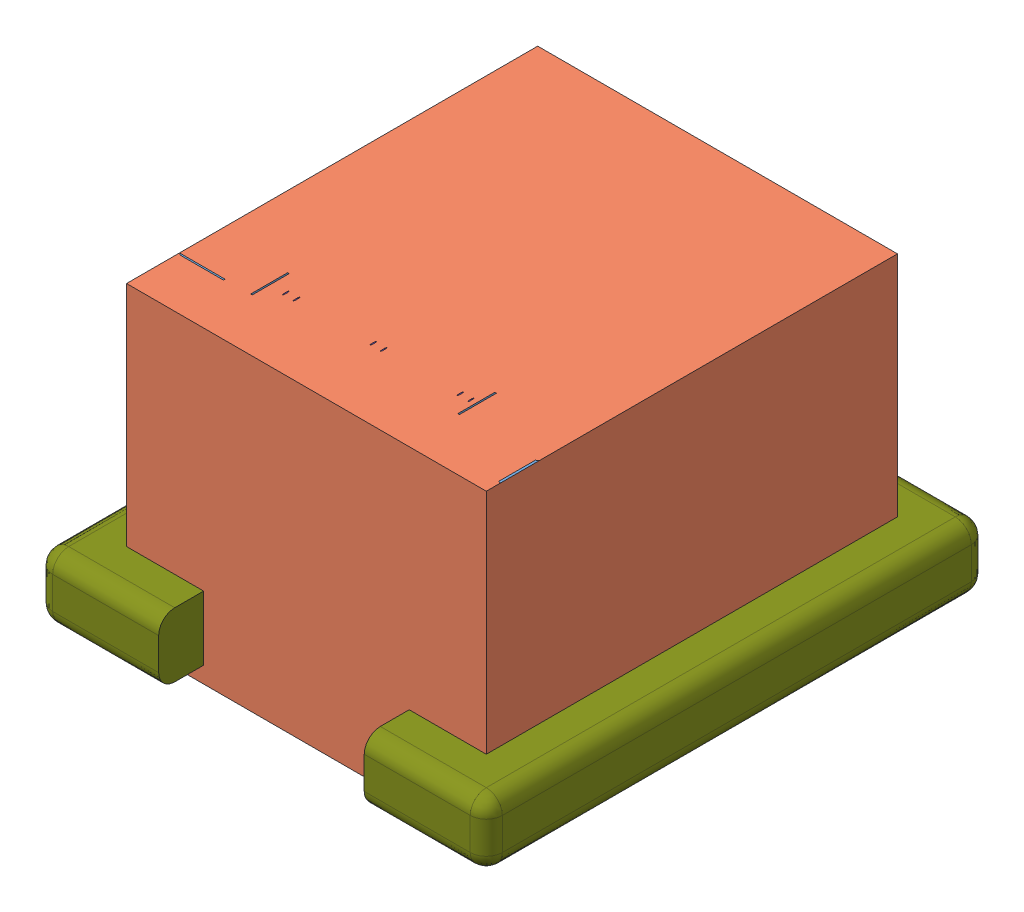
SolidWorks assembly BottyPotty, configuration Default. Lengths in mm.
Overall size (889 639.7 990.6).
139 component instances, 34 part files, 31 mates.
Components (placement in the parent):
- Gear Bit-1: Gear Bit [Default] at (72.3018 220.1757 180.7351) size (711.2 482.6 76.2)
- BoxBot-1: BoxBot [Default] at (72.3018 251.9257 -158.9899) size (711.2 609.6 812.8)
- Fuel-1: Fuel [Default] at (72.3018 234.1474 -212.6616) size (127 127 127)
- Bin-1: Bin [Default] at (72.3018 315.4257 -311.3899) size (711.2 482.6 508)
- Climby Bit-1: Climby Bit [Default] at (72.3018 137.6257 -463.7899) size (304.8 127 203.2)
- Gear-1: Gear [Default] at (72.3018 207.6033 181.9111) size (279.4 279.4 50.8)
- Collection-1: Collection [Default] at (-247.2786 -102.69 264.2469) x (0 0 -1) z (1 0 0) size (103.22 501.51 473.08)
  - HexRod-1: HexRod [Default] at (158.1244 213.3282 311.0594) size (12.7 14.66 406.4)
  - wheelpulley-1: wheelpulley [Default] at (101.3185 233.0041 546.741) x (0 0 -1) z (0.052324 -0.99863 0) size (42.43 76.75 76.75)
    - pulley-1: pulley [Default] at (45.3639 55.6985 22.6212) size (13 74.23 74.23)
    - pulley-2: pulley [Default] at (62.0263 55.6985 22.6212) x (-1 0 0) z (0 0.000084 1) size (13 74.23 74.23)
    - wheel-1: wheel [Default] at (70.1462 55.6985 22.6212) x (1 0 0) z (0 -0.99863 -0.052324) size (9.53 73.03 73.03)
    - wheel-2: wheel [Default] at (37.244 55.6985 22.6212) x (1 0 0) z (0 -0.99863 -0.052324) size (9.53 73.03 73.03)
  - wheelpulley-2: wheelpulley [Default] at (101.3185 233.0041 374.275) x (0 0 -1) z (0.052324 -0.99863 0) size (42.43 76.75 76.75)
    - pulley-1: pulley [Default] at (45.3639 55.6985 22.6212) size (13 74.23 74.23)
    - pulley-2: pulley [Default] at (62.0263 55.6985 22.6212) x (-1 0 0) z (0 0.000084 1) size (13 74.23 74.23)
    - wheel-1: wheel [Default] at (70.1462 55.6985 22.6212) x (1 0 0) z (0 -0.99863 -0.052324) size (9.53 73.03 73.03)
    - wheel-2: wheel [Default] at (37.244 55.6985 22.6212) x (1 0 0) z (0 -0.99863 -0.052324) size (9.53 73.03 73.03)
  - wheelpulley-3: wheelpulley [Default] at (101.3185 233.0041 201.809) x (0 0 -1) z (0.052324 -0.99863 0) size (42.43 76.75 76.75)
    - pulley-1: pulley [Default] at (45.3639 55.6985 22.6212) size (13 74.23 74.23)
    - pulley-2: pulley [Default] at (62.0263 55.6985 22.6212) x (-1 0 0) z (0 0.000084 1) size (13 74.23 74.23)
    - wheel-1: wheel [Default] at (70.1462 55.6985 22.6212) x (1 0 0) z (0 -0.99863 -0.052324) size (9.53 73.03 73.03)
    - wheel-2: wheel [Default] at (37.244 55.6985 22.6212) x (1 0 0) z (0 -0.99863 -0.052324) size (9.53 73.03 73.03)
  - wheelplate-1: wheelplate [Default] at (158.1244 213.3282 515.8469) x (0 0 -1) z (1 0 0) size (3.17 482.6 73.03)
  - wheelplate-2: wheelplate [Default] at (158.1244 213.3282 106.2719) x (0 0 -1) z (1 0 0) size (3.17 482.6 73.03)
  - CollectSub-1: CollectSub [Default] at (376.0703 456.2047 78.0182) size (103.22 103.22 450.86)
    - HexRod-1: HexRod [Default] at (-217.9459 166.6985 296.5412) size (12.7 14.66 406.4)
    - wheelpulley-1: wheelpulley [Default] at (-263.3886 127.3412 468.7227) x (0 0 -1) z (0.891001 -0.454001 0) size (42.43 76.75 76.75)
      - pulley-1: pulley [Default] at (45.3639 55.6985 22.6212) size (13 74.23 74.23)
      - pulley-2: pulley [Default] at (62.0263 55.6985 22.6212) x (-1 0 0) z (0 0.000084 1) size (13 74.23 74.23)
      - wheel-1: wheel [Default] at (70.1462 55.6985 22.6212) x (1 0 0) z (0 -0.99863 -0.052324) size (9.53 73.03 73.03)
      - wheel-2: wheel [Default] at (37.244 55.6985 22.6212) x (1 0 0) z (0 -0.99863 -0.052324) size (9.53 73.03 73.03)
    - wheelpulley-2: wheelpulley [Default] at (-263.3886 127.3412 296.2567) x (0 0 -1) z (0.891001 -0.454001 0) size (42.43 76.75 76.75)
      - pulley-1: pulley [Default] at (45.3639 55.6985 22.6212) size (13 74.23 74.23)
      - pulley-2: pulley [Default] at (62.0263 55.6985 22.6212) x (-1 0 0) z (0 0.000084 1) size (13 74.23 74.23)
      - wheel-1: wheel [Default] at (70.1462 55.6985 22.6212) x (1 0 0) z (0 -0.99863 -0.052324) size (9.53 73.03 73.03)
      - wheel-2: wheel [Default] at (37.244 55.6985 22.6212) x (1 0 0) z (0 -0.99863 -0.052324) size (9.53 73.03 73.03)
    - wheelpulley-3: wheelpulley [Default] at (-263.3886 127.3412 123.7907) x (0 0 -1) z (0.891001 -0.454001 0) size (42.43 76.75 76.75)
      - pulley-1: pulley [Default] at (45.3639 55.6985 22.6212) size (13 74.23 74.23)
      - pulley-2: pulley [Default] at (62.0263 55.6985 22.6212) x (-1 0 0) z (0 0.000084 1) size (13 74.23 74.23)
      - wheel-1: wheel [Default] at (70.1462 55.6985 22.6212) x (1 0 0) z (0 -0.99863 -0.052324) size (9.53 73.03 73.03)
      - wheel-2: wheel [Default] at (37.244 55.6985 22.6212) x (1 0 0) z (0 -0.99863 -0.052324) size (9.53 73.03 73.03)
  - Belt-gates 10mm wide-2: Belt-gates 10mm wide [Default] at (158.1371 418.0522 319.5804) x (0 0 1) z (0.000062 -1 0) size (15 69.9 479.58)
  - Belt-gates 10mm wide-3: Belt-gates 10mm wide [Default] at (158.1371 418.0522 491.638) x (0 0 1) z (0.000062 -1 0) size (15 69.9 479.58)
  - Belt-gates 10mm wide-4: Belt-gates 10mm wide [Default] at (158.1371 418.0522 149.5217) x (0 0 1) z (0.000062 -1 0) size (15 69.9 479.58)
- ball ramp-1: ball ramp [Default] at (72.3018 110.6382 106.1226) size (711.2 452.32 91.84)
- 2017 electronics plate-1: 2017 electronics plate [Default] at (72.3018 42.3757 -311.3899) x (1 0 0) z (0 0 -1) size (711.2 41.27 812.8)
  - electronics plate-1: electronics plate [Default] at origin size (711.2 3.17 812.8)
  - Victor-SP-Motor-controller-20217-9090-1: Victor-SP-Motor-controller-20217-9090 [Default] at (-258.5801 9.1448 -219.6738) size (30.24 20.93 144.78)
  - Victor-SP-Motor-controller-20217-9090-3: Victor-SP-Motor-controller-20217-9090 [Default] at (-215.4001 9.1448 -219.6738) size (30.24 20.93 144.78)
  - Victor-SP-Motor-controller-20217-9090-4: Victor-SP-Motor-controller-20217-9090 [Default] at (-172.2201 9.1448 -219.6738) size (30.24 20.93 144.78)
  - Victor-SP-Motor-controller-20217-9090-5: Victor-SP-Motor-controller-20217-9090 [Default] at (-129.0401 9.1448 -219.6738) size (30.24 20.93 144.78)
  - VoltReg-217-4245-1: VoltReg-217-4245 [Default] at (-39.4381 10.281 -153.6848) size (56.39 19.92 51.56)
  - RouterCrude-1: RouterCrude [Default] at (37.6355 15.875 -155.8516) size (66.67 25.4 92.08)
  - PowerDistribution-1: PowerDistribution [Default] at (-149.0064 9.8552 -39.9983) x (-1 0 0) z (0 0 -1) size (192.68 36.15 120.93)
  - Victor-SP-Motor-controller-20217-9090-9: Victor-SP-Motor-controller-20217-9090 [Default] at (122.4199 9.1448 -219.6738) size (30.24 20.93 144.78)
  - Victor-SP-Motor-controller-20217-9090-10: Victor-SP-Motor-controller-20217-9090 [Default] at (165.5999 9.1448 -219.6738) size (30.24 20.93 144.78)
  - Victor-SP-Motor-controller-20217-9090-11: Victor-SP-Motor-controller-20217-9090 [Default] at (208.7799 9.1448 -219.6738) size (30.24 20.93 144.78)
  - Victor-SP-Motor-controller-20217-9090-12: Victor-SP-Motor-controller-20217-9090 [Default] at (251.9599 9.1448 -219.6738) size (30.24 20.93 144.78)
  - RoboRIO-1: RoboRIO [Default] at (170.9718 13.675 -32.4938) x (0.999904 0 0.013829) z (-0.013829 0 0.999904) size (147 34 144)
- Drive Side 32- version current 1-20-17-1: Drive Side 32- version current 1-20-17 [Default] at (333.5386 -44.9466 -117.3546) x (0 0 1) z (0 1 0) size (812.8 264.42 101.6)
  - Part 1_1-1: Part 1_1 [Default] at (-41.6353 24.5131 42.8723) size (812.8 6.35 82.55)
  - Part 1_1_2-1: Part 1_1_2 [Default] at (-41.6353 94.3631 42.8723) size (812.8 6.35 82.55)
  - Part 5_1-1: Part 5_1 [Default] at (-293.1186 5.1631 48.3276) x (0 0 -1) z (1 0 0) size (62.86 145.05 62.86)
  - Part 5_1-2: Part 5_1 [Default] at (-47.0906 5.1631 32.689) size (62.86 145.05 62.86)
  - am-0255 2.5inch CIM Motor_1-1: am-0255 2.5inch CIM Motor_1 [Default] at (-318.4953 -64.3869 152.1685) x (1 0 0) z (0 1 0) size (64.01 64.01 154.94)
  - am-0255 2.5inch CIM Motor_1-2: am-0255 2.5inch CIM Motor_1 [Default] at (-77.1953 -64.3869 152.1685) x (1 0 0) z (0 1 0) size (64.01 64.01 154.94)
  - 4 in tread_1-1: 4 in tread_1 [Default] at (-282.9353 63.8121 42.8723) x (0 1 0) z (0 0 1) size (25.4 101.6 101.6)
  - 4in 2013 Hub_1-1: 4in 2013 Hub_1 [Default] at (-282.9353 63.8121 42.8723) x (0 1 0) z (1 0 0) size (17.56 82.55 82.55)
  - 4in 2013 Hub_1_2-1: 4in 2013 Hub_1_2 [Default] at (-282.9353 63.8121 42.8723) x (0 1 0) z (1 0 0) size (17.56 82.55 82.55)
  - 4 in tread_1-2: 4 in tread_1 [Default] at (-41.6353 67.1549 42.8723) x (0 -1 0) z (0 0 1) size (25.4 101.6 101.6)
  - 4in 2013 Hub_1-2: 4in 2013 Hub_1 [Default] at (-41.6353 67.1549 42.8723) x (0 1 0) z (1 0 0) size (17.56 82.55 82.55)
  - 4in 2013 Hub_1_2-2: 4in 2013 Hub_1_2 [Default] at (-41.6353 67.1549 42.8723) x (0 1 0) z (1 0 0) size (17.56 82.55 82.55)
  - am-0030 0.5''''id Flanged, Shielded Ball Bearing (FR8ZZ)_1-1: am-0030 0.5''''id Flanged, Shielded Ball Bearing (FR8ZZ)_1 [Default] at (-41.6353 94.4165 42.8723) x (1 0 0) z (0 -1 0) size (31.12 31.12 7.93)
  - am-0030 0.5''''id Flanged, Shielded Ball Bearing (FR8ZZ)_1-2: am-0030 0.5''''id Flanged, Shielded Ball Bearing (FR8ZZ)_1 [Default] at (-41.6353 18.1098 42.8723) x (1 0 0) z (0 1 0) size (31.12 31.12 7.93)
  - am-0030 0.5''''id Flanged, Shielded Ball Bearing (FR8ZZ)_1-3: am-0030 0.5''''id Flanged, Shielded Ball Bearing (FR8ZZ)_1 [Default] at (-282.9353 94.4165 42.8723) x (1 0 0) z (0 -1 0) size (31.12 31.12 7.93)
  - P60 bearing block_1-1: P60 bearing block_1 [Default] at (184.6301 84.0337 22.2734) x (0 1 0) z (1 0 0) size (9.02 38.25 38.25)
  - R8ZZ Bearing_1-1: R8ZZ Bearing_1 [Default] at (220.2635 84.3512 27.8377) x (0 1 0) z (0 0 1) size (7.94 28.58 28.58)
  - P60 bearing block_1-2: P60 bearing block_1 [Default] at (184.6301 28.4926 63.4711) x (0 -1 0) z (1 0 0) size (9.02 38.25 38.25)
  - R8ZZ Bearing_1-2: R8ZZ Bearing_1 [Default] at (220.2635 139.9137 27.8377) x (0 1 0) z (0 0 1) size (7.94 28.58 28.58)
  - 500 Key Hub r2_1-1: 500 Key Hub r2_1 [Default] at (-282.9353 80.3856 42.8723) x (-1 0 0) z (0 1 0) size (57.15 57.15 25.4)
  - 500 Key Hub r2_1-2: 500 Key Hub r2_1 [Default] at (-41.6353 50.5814 42.8723) x (1 0 0) z (0 -1 0) size (57.15 57.15 25.4)
  - 500 Key Hub r2_1-3: 500 Key Hub r2_1 [Default] at (-282.9353 47.2386 42.8723) x (1 0 0) z (0 -1 0) size (57.15 57.15 25.4)
  - 500 Key Hub r2_1-4: 500 Key Hub r2_1 [Default] at (-41.6353 83.7284 42.8723) x (-1 0 0) z (0 1 0) size (57.15 57.15 25.4)
  - am-0030 0.5''''id Flanged, Shielded Ball Bearing (FR8ZZ)_1-4: am-0030 0.5''''id Flanged, Shielded Ball Bearing (FR8ZZ)_1 [Default] at (-282.9353 18.1098 42.8723) x (1 0 0) z (0 1 0) size (31.12 31.12 7.93)
  - 217-2736.20121205_1-1: 217-2736.20121205_1 [Default] at (-37.0221 40.4543 45.4879) x (1 0 0) z (0 1 0) size (25.39 25.4 6.35)
  - 217-2736.20121205_1-2: 217-2736.20121205_1 [Default] at (-37.0221 93.8554 40.2567) x (1 0 0) z (0 -1 0) size (25.39 25.4 6.35)
  - 217-2736.20121205_1-3: 217-2736.20121205_1 [Default] at (-278.3221 37.1115 45.4879) x (1 0 0) z (0 1 0) size (25.39 25.4 6.35)
  - 217-2736.20121205_1-4: 217-2736.20121205_1 [Default] at (-278.3221 90.5127 40.2567) x (1 0 0) z (0 -1 0) size (25.39 25.4 6.35)
  - am-churro 500 churro tube_1-1: am-churro 500 churro tube_1 [Default] at (-435.3353 24.5131 68.9073) x (1 0 0) z (0 1 0) size (14.66 12.7 63.5)
  - am-churro 500 churro tube_1-2: am-churro 500 churro tube_1 [Default] at (-435.3353 24.5131 16.8373) x (1 0 0) z (0 1 0) size (14.66 12.7 63.5)
  - am-churro 500 churro tube_1-3: am-churro 500 churro tube_1 [Default] at (352.0647 24.5131 68.9073) x (1 0 0) z (0 1 0) size (14.66 12.7 63.5)
  - am-churro 500 churro tube_1-4: am-churro 500 churro tube_1 [Default] at (352.0647 24.5131 16.8373) x (1 0 0) z (0 1 0) size (14.66 12.7 63.5)
  - am-churro 500 churro tube_1-5: am-churro 500 churro tube_1 [Default] at (-162.2853 24.5131 16.8373) x (1 0 0) z (0 1 0) size (14.66 12.7 63.5)
  - am-churro 500 churro tube_1-6: am-churro 500 churro tube_1 [Default] at (79.0147 24.5131 68.9073) x (1 0 0) z (0 1 0) size (14.66 12.7 63.5)
  - am-churro 500 churro tube_1-7: am-churro 500 churro tube_1 [Default] at (79.0147 24.5131 16.8373) x (1 0 0) z (0 1 0) size (14.66 12.7 63.5)
  - am-churro 500 churro tube_1-8: am-churro 500 churro tube_1 [Default] at (-162.2853 24.5131 68.9073) x (1 0 0) z (0 1 0) size (14.66 12.7 63.5)
- Drive Side 32- version current 1-20-17-2: Drive Side 32- version current 1-20-17 [Default] at (-188.9351 40.798 -117.3546) x (0 0 1) z (0 -1 0) size (812.8 264.42 101.6)
  - Part 1_1-1: Part 1_1 [Default] at (-41.6353 24.5131 42.8723) size (812.8 6.35 82.55)
  - Part 1_1_2-1: Part 1_1_2 [Default] at (-41.6353 94.3631 42.8723) size (812.8 6.35 82.55)
  - Part 5_1-1: Part 5_1 [Default] at (-293.1186 5.1631 48.3276) x (0 0 -1) z (1 0 0) size (62.86 145.05 62.86)
  - Part 5_1-2: Part 5_1 [Default] at (-47.0906 5.1631 32.689) size (62.86 145.05 62.86)
  - am-0255 2.5inch CIM Motor_1-1: am-0255 2.5inch CIM Motor_1 [Default] at (-318.4953 -64.3869 152.1685) x (1 0 0) z (0 1 0) size (64.01 64.01 154.94)
  - am-0255 2.5inch CIM Motor_1-2: am-0255 2.5inch CIM Motor_1 [Default] at (-77.1953 -64.3869 152.1685) x (1 0 0) z (0 1 0) size (64.01 64.01 154.94)
  - 4 in tread_1-1: 4 in tread_1 [Default] at (-282.9353 63.8121 42.8723) x (0 1 0) z (0 0 1) size (25.4 101.6 101.6)
  - 4in 2013 Hub_1-1: 4in 2013 Hub_1 [Default] at (-282.9353 63.8121 42.8723) x (0 1 0) z (1 0 0) size (17.56 82.55 82.55)
  - 4in 2013 Hub_1_2-1: 4in 2013 Hub_1_2 [Default] at (-282.9353 63.8121 42.8723) x (0 1 0) z (1 0 0) size (17.56 82.55 82.55)
  - 4 in tread_1-2: 4 in tread_1 [Default] at (-41.6353 67.1549 42.8723) x (0 -1 0) z (0 0 1) size (25.4 101.6 101.6)
  - 4in 2013 Hub_1-2: 4in 2013 Hub_1 [Default] at (-41.6353 67.1549 42.8723) x (0 1 0) z (1 0 0) size (17.56 82.55 82.55)
  - 4in 2013 Hub_1_2-2: 4in 2013 Hub_1_2 [Default] at (-41.6353 67.1549 42.8723) x (0 1 0) z (1 0 0) size (17.56 82.55 82.55)
  - am-0030 0.5''''id Flanged, Shielded Ball Bearing (FR8ZZ)_1-1: am-0030 0.5''''id Flanged, Shielded Ball Bearing (FR8ZZ)_1 [Default] at (-41.6353 94.4165 42.8723) x (1 0 0) z (0 -1 0) size (31.12 31.12 7.93)
  - am-0030 0.5''''id Flanged, Shielded Ball Bearing (FR8ZZ)_1-2: am-0030 0.5''''id Flanged, Shielded Ball Bearing (FR8ZZ)_1 [Default] at (-41.6353 18.1098 42.8723) x (1 0 0) z (0 1 0) size (31.12 31.12 7.93)
  - am-0030 0.5''''id Flanged, Shielded Ball Bearing (FR8ZZ)_1-3: am-0030 0.5''''id Flanged, Shielded Ball Bearing (FR8ZZ)_1 [Default] at (-282.9353 94.4165 42.8723) x (1 0 0) z (0 -1 0) size (31.12 31.12 7.93)
  - P60 bearing block_1-1: P60 bearing block_1 [Default] at (184.6301 84.0337 22.2734) x (0 1 0) z (1 0 0) size (9.02 38.25 38.25)
  - R8ZZ Bearing_1-1: R8ZZ Bearing_1 [Default] at (220.2635 84.3512 27.8377) x (0 1 0) z (0 0 1) size (7.94 28.58 28.58)
  - P60 bearing block_1-2: P60 bearing block_1 [Default] at (184.6301 28.4926 63.4711) x (0 -1 0) z (1 0 0) size (9.02 38.25 38.25)
  - R8ZZ Bearing_1-2: R8ZZ Bearing_1 [Default] at (220.2635 139.9137 27.8377) x (0 1 0) z (0 0 1) size (7.94 28.58 28.58)
  - 500 Key Hub r2_1-1: 500 Key Hub r2_1 [Default] at (-282.9353 80.3856 42.8723) x (-1 0 0) z (0 1 0) size (57.15 57.15 25.4)
  - 500 Key Hub r2_1-2: 500 Key Hub r2_1 [Default] at (-41.6353 50.5814 42.8723) x (1 0 0) z (0 -1 0) size (57.15 57.15 25.4)
  - 500 Key Hub r2_1-3: 500 Key Hub r2_1 [Default] at (-282.9353 47.2386 42.8723) x (1 0 0) z (0 -1 0) size (57.15 57.15 25.4)
  - 500 Key Hub r2_1-4: 500 Key Hub r2_1 [Default] at (-41.6353 83.7284 42.8723) x (-1 0 0) z (0 1 0) size (57.15 57.15 25.4)
  - am-0030 0.5''''id Flanged, Shielded Ball Bearing (FR8ZZ)_1-4: am-0030 0.5''''id Flanged, Shielded Ball Bearing (FR8ZZ)_1 [Default] at (-282.9353 18.1098 42.8723) x (1 0 0) z (0 1 0) size (31.12 31.12 7.93)
  - 217-2736.20121205_1-1: 217-2736.20121205_1 [Default] at (-37.0221 40.4543 45.4879) x (1 0 0) z (0 1 0) size (25.39 25.4 6.35)
  - 217-2736.20121205_1-2: 217-2736.20121205_1 [Default] at (-37.0221 93.8554 40.2567) x (1 0 0) z (0 -1 0) size (25.39 25.4 6.35)
  - 217-2736.20121205_1-3: 217-2736.20121205_1 [Default] at (-278.3221 37.1115 45.4879) x (1 0 0) z (0 1 0) size (25.39 25.4 6.35)
  - 217-2736.20121205_1-4: 217-2736.20121205_1 [Default] at (-278.3221 90.5127 40.2567) x (1 0 0) z (0 -1 0) size (25.39 25.4 6.35)
  - am-churro 500 churro tube_1-1: am-churro 500 churro tube_1 [Default] at (-435.3353 24.5131 68.9073) x (1 0 0) z (0 1 0) size (14.66 12.7 63.5)
  - am-churro 500 churro tube_1-2: am-churro 500 churro tube_1 [Default] at (-435.3353 24.5131 16.8373) x (1 0 0) z (0 1 0) size (14.66 12.7 63.5)
  - am-churro 500 churro tube_1-3: am-churro 500 churro tube_1 [Default] at (352.0647 24.5131 68.9073) x (1 0 0) z (0 1 0) size (14.66 12.7 63.5)
  - am-churro 500 churro tube_1-4: am-churro 500 churro tube_1 [Default] at (352.0647 24.5131 16.8373) x (1 0 0) z (0 1 0) size (14.66 12.7 63.5)
  - am-churro 500 churro tube_1-5: am-churro 500 churro tube_1 [Default] at (-162.2853 24.5131 16.8373) x (1 0 0) z (0 1 0) size (14.66 12.7 63.5)
  - am-churro 500 churro tube_1-6: am-churro 500 churro tube_1 [Default] at (79.0147 24.5131 68.9073) x (1 0 0) z (0 1 0) size (14.66 12.7 63.5)
  - am-churro 500 churro tube_1-7: am-churro 500 churro tube_1 [Default] at (79.0147 24.5131 16.8373) x (1 0 0) z (0 1 0) size (14.66 12.7 63.5)
  - am-churro 500 churro tube_1-8: am-churro 500 churro tube_1 [Default] at (-162.2853 24.5131 68.9073) x (1 0 0) z (0 1 0) size (14.66 12.7 63.5)
- CircutBreaker-1: CircutBreaker [Default] at (270.1558 385.2555 116.0417) x (0 -1 0) z (0 0 1) size (73.72 42.2 48.95)
- Battery-2: Battery [Default] at (90.2065 128.4467 -541.2594) x (-1 0 0) z (0 0 -1) size (177.8 165.1 76.2)
- HexRod-1: HexRod [Default] at (40.5606 -60.5472 -112.6701) x (0 0 -1) z (1 0 0) size (12.7 14.66 406.4)
- bumper-1: bumper [Default] at (-372.1982 42.8866 -158.9899) size (241.3 127 990.6)
- bumper-2: bumper [Default] at (516.8018 42.8866 -158.9899) x (-1 0 0) z (0 0 -1) size (241.3 127 990.6)
Mates (geometry in assembly coordinates):
- Coincident6: coincident aligned: plane of Gear Bit-1 through (72.3018 220.1757 180.7351) normal (1 0 0); plane of BoxBot-1 through (72.3018 251.9257 -158.9899) normal (1 0 0)
- Coincident10: coincident aligned: plane of Gear Bit-1 through (72.3018 220.1757 180.7351) normal (1 0 0); plane of Fuel-1 through (72.3018 234.1474 -212.6616) normal (1 0 0)
- Coincident12: coincident aligned: plane of BoxBot-1 through (427.9018 556.7257 -565.3899) normal (1 0 0); plane of Bin-1 through (427.9018 556.7257 -565.3899) normal (1 0 0)
- Coincident13: coincident aligned: line of BoxBot-1 through (427.9018 556.7257 247.4101) axis (0 0 -1); line of Bin-1 through (427.9018 556.7257 -57.3899) axis (0 0 -1)
- Coincident15: coincident aligned: plane of BoxBot-1 through (-283.2982 556.7257 -565.3899) normal (0 0 -1); plane of Bin-1 through (-283.2982 556.7257 -565.3899) normal (0 0 -1)
- Coincident22: coincident aligned: plane of Bin-1 through (72.3018 315.4257 -311.3899) normal (1 0 0); plane of Climby Bit-1 through (72.3018 137.6257 -463.7899) normal (1 0 0)
- Coincident23: coincident aligned: plane of BoxBot-1 through (-283.2982 556.7257 -565.3899) normal (0 0 -1); plane of Climby Bit-1 through (-80.0982 201.1257 -565.3899) normal (0 0 -1)
- Coincident24: coincident: line of Bin-1 through (427.9018 74.1257 -565.3899) axis (-1 0 0); plane of Climby Bit-1 through (72.3018 74.1257 -463.7899) normal (0 -1 0)
- Coincident27: coincident aligned: plane of Climby Bit-1 through (72.3018 137.6257 -463.7899) normal (1 0 0); plane of Gear-1 through (72.3018 207.6033 181.9111) normal (1 0 0)
- Coincident48: coincident aligned: plane of Gear Bit-1 through (-283.2982 556.7257 218.8351) normal (0 1 0); plane of BoxBot-1 through (72.3018 556.7257 -158.9899) normal (0 1 0)
- Coincident54: coincident anti-aligned: plane of Gear Bit-1 through (72.3018 220.1757 142.6351) normal (0 0 -1); plane of Collection-1/wheelplate-1 through (266.9808 556.7257 142.6351) normal (0 0 1)
- Distance2: distance = 127 mm: plane of Collection-1/wheelplate-1 through (266.9808 556.7257 69.6101) normal (0 0 -1); line of Bin-1 through (427.9018 556.7257 -57.3899) axis (0 -1 0)
- Coincident57: coincident: plane of BoxBot-1 through (72.3018 556.7257 -158.9899) normal (0 1 0); line of Collection-1/wheelplate-1 through (270.1558 556.7257 142.6351) axis (0 0 -1)
- Coincident58: coincident aligned: plane of BoxBot-1 through (427.9018 556.7257 -565.3899) normal (1 0 0); plane of ball ramp-1 through (427.9018 423.3757 -46.2774) normal (1 0 0)
- Parallel5: parallel aligned: plane of ball ramp-1 through (275.5018 110.6382 -44.6899) normal (0 0 1); plane of assembly through (0 0 0) normal (0 0 1)
- Coincident61: coincident: plane of BoxBot-1 through (72.3018 556.7257 -158.9899) normal (0 1 0); line of Collection-1/wheelplate-2 through (-142.5942 556.7257 142.6351) axis (0 0 -1)
- Coincident62: coincident aligned: plane of Climby Bit-1 through (72.3018 137.6257 -463.7899) normal (1 0 0); plane of Collection-1/Belt-gates 10mm wide-2
- Concentric2: concentric anti-aligned: cylinder of Collection-1/wheelpulley-1/wheel-2 through (257.4558 110.6382 106.1226) axis (1 0 0) radius 36.5125; cylinder of ball ramp-1 through (275.5018 110.6382 106.1226) axis (-1 0 0) radius 150.8125
- Coincident68: coincident anti-aligned: line of BoxBot-1 through (-283.2982 556.7257 -565.3899) axis (0 -1 0); line of 2017 electronics plate-1/electronics plate-1 through (-283.2982 39.2007 -565.3899) axis (0 1 0)
- Coincident69: coincident anti-aligned: line of BoxBot-1 through (-283.2982 556.7257 -565.3899) axis (0 -1 0); line of Drive Side 32- version current 1-20-17-2/Part 1_1_2-1 through (-283.2982 -43.3493 -565.3899) axis (0 1 0)
- Coincident72: coincident aligned: line of BoxBot-1 through (427.9018 556.7257 -565.3899) axis (0 -1 0); line of Drive Side 32- version current 1-20-17-1/Part 1_1_2-1 through (427.9018 39.2007 -565.3899) axis (0 -1 0)
- Coincident74: coincident: line of 2017 electronics plate-1/electronics plate-1 through (427.9018 39.2007 -565.3899) axis (0 0 1); plane of Drive Side 32- version current 1-20-17-1/Part 1_1_2-1 through (427.9018 -2.0743 -158.9899) normal (1 0 0)
- Coincident75: coincident anti-aligned: line of 2017 electronics plate-1/electronics plate-1 through (427.9018 39.2007 -565.3899) axis (0 0 1); line of Drive Side 32- version current 1-20-17-1/Part 1_1_2-1 through (427.9018 39.2007 247.4101) axis (0 0 -1)
- Coincident76: coincident anti-aligned: plane of Collection-1/wheelplate-1 through (270.1558 110.6382 106.1226) normal (1 0 0); plane of CircutBreaker-1 through (270.1558 348.4255 116.0417) normal (-1 0 0)
- Coincident79: coincident anti-aligned: plane of Drive Side 32- version current 1-20-17-2/Part 1_1_2-1 through (-283.2982 -2.0743 -158.9899) normal (-1 0 0); plane of bumper-1 through (-283.2982 106.3866 -565.3899) normal (1 0 0)
- Coincident80: coincident anti-aligned: plane of BoxBot-1 through (-283.2982 556.7257 247.4101) normal (0 0 1); plane of bumper-1 through (-130.8982 106.3866 247.4101) normal (0 0 -1)
- Coincident82: coincident anti-aligned: plane of Drive Side 32- version current 1-20-17-1/Part 1_1_2-1 through (427.9018 -2.0743 -158.9899) normal (1 0 0); plane of bumper-2 through (427.9018 106.3866 247.4101) normal (-1 0 0)
- Coincident84: coincident aligned: plane of bumper-1 through (-372.1982 -20.6134 -158.9899) normal (0 -1 0); plane of bumper-2 through (516.8018 -20.6134 -158.9899) normal (0 -1 0)
- Coincident85: coincident aligned: plane of bumper-1 through (-372.1982 106.3866 336.3101) normal (0 0 1); plane of bumper-2 through (516.8018 106.3866 336.3101) normal (0 0 1)
- Tangent1: tangent aligned: plane of BoxBot-1 through (72.3018 -52.8743 -158.9899) normal (0 -1 0); cylinder of Drive Side 32- version current 1-20-17-2/4 in tread_1-1 through (-240.0472 -2.0743 -400.2899) axis (1 0 0) radius 50.8
- Coincident86: coincident anti-aligned: plane of 2017 electronics plate-1/electronics plate-1 through (72.3018 39.2007 -311.3899) normal (0 -1 0); plane of Drive Side 32- version current 1-20-17-2/Part 1_1-1 through (-207.0982 39.2007 -158.9899) normal (0 1 0)
